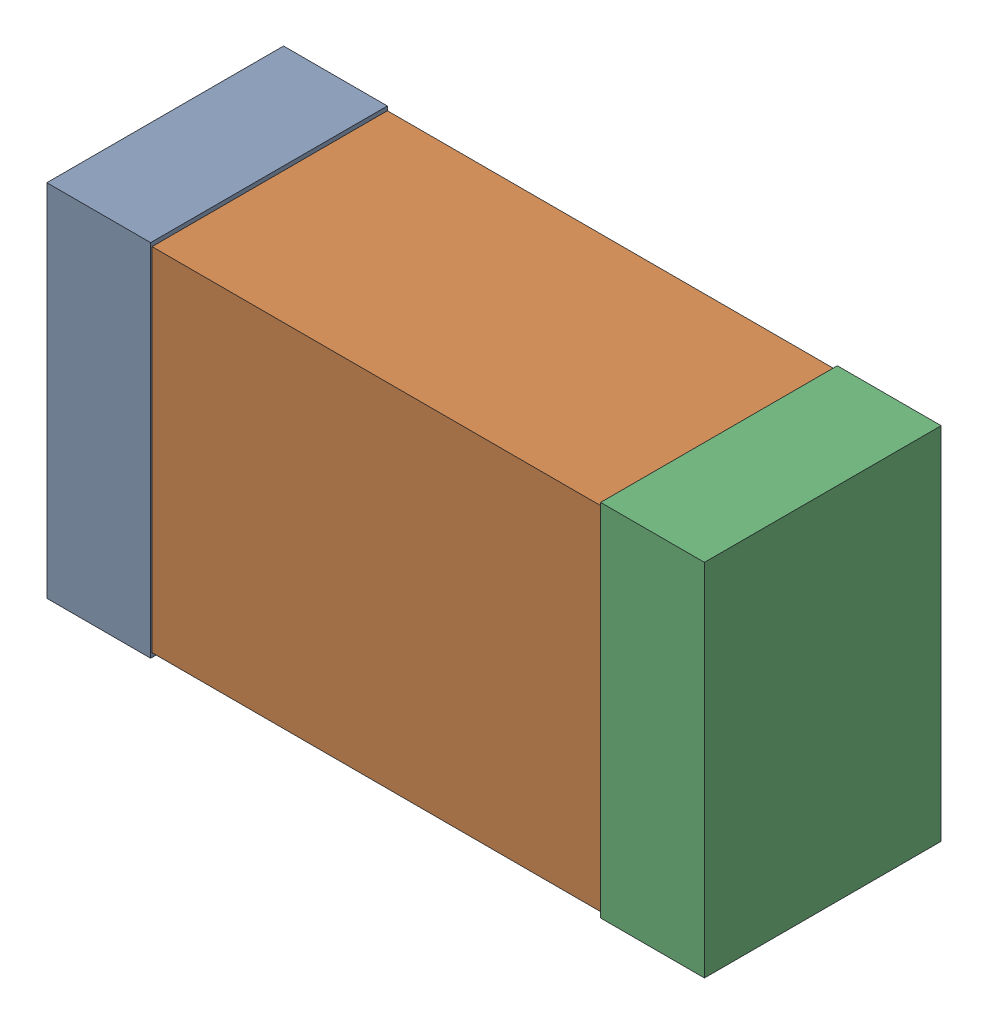
SolidWorks assembly RFBBKanaloa_v2.0.0_Power, configuration Default. Lengths in mm.
Overall size (2.38 1.3 0.85).
6 component instances, 2 part files, 0 mates.
Components (placement in the parent):
- 352877648-1: 352877648 [Default] at (44.974 54.102 0) size (0.38 1.3 0.85)
  - Extruded_14-1: Extruded_14 [Default] at origin size (0.38 1.3 0.85)
- 352877392-1: 352877392 [Default] at (45.974 54.102 0) size (2.2 1.27 0.85)
  - Extruded_15-1: Extruded_15 [Default] at origin size (2.2 1.27 0.85)
- 352877648-2: 352877648 [Default] at (46.974 54.102 0) size (0.38 1.3 0.85)
  - Extruded_14-1: Extruded_14 [Default] at origin size (0.38 1.3 0.85)
